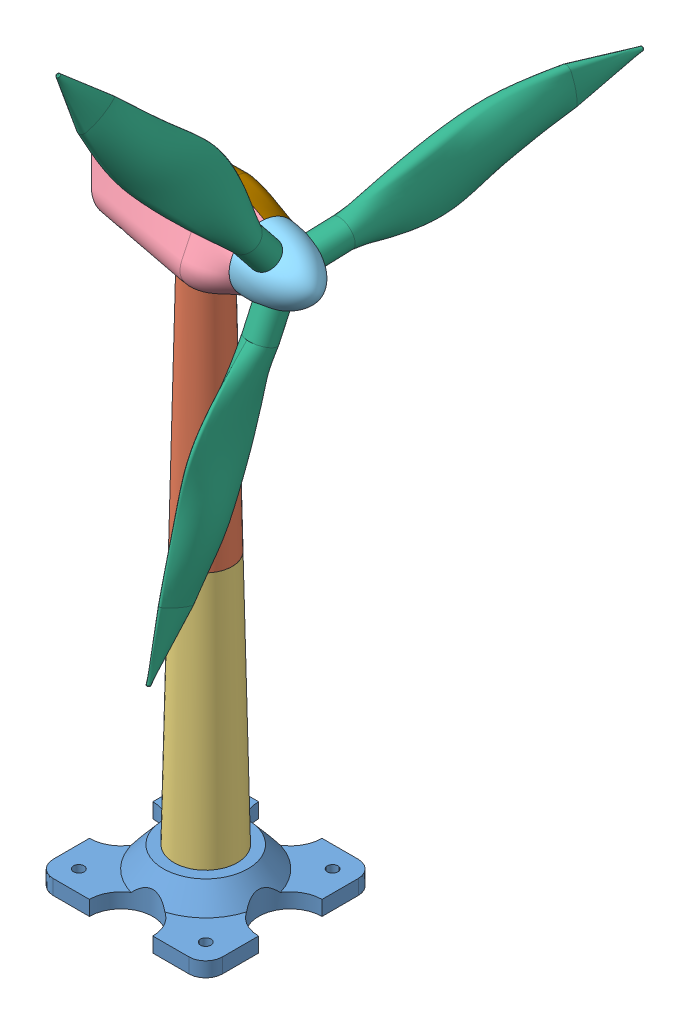
SolidWorks assembly Assem1, configuration Default. Lengths in mm.
Overall size (156.03 521.01 338.75).
12 component instances, 9 part files, 19 mates.
Components (placement in the parent):
- 1.Base-1: 1.Base [Default] at (0 0 89.5274) size (101.6 21.59 101.6)
- 5.Upper Mast-1: 5.Upper Mast [Default] at (0 173.99 89.5274) x (0 1 0) z (-0.807712 0 0.589577) size (165.1 31.76 31.76)
- Lower Mast-1: Lower Mast [Default] at (0 8.89 89.5274) x (0 1 0) z (0 0 1) size (165.1 38.1 38.1)
- 9.housing-1: 9.housing [Default] at (14.0969 349.25 91.06) x (0.108083 0 -0.994142) z (0.994142 0 0.108083) size (31.53 51.06 103.55)
- 2.Rotar-1: 2.Rotar [Default] at (39.3481 349.25 93.8053) x (-0.994142 0 -0.108083) z (0.015527 -0.989627 -0.142821) size (36.1 38.53 38.1)
- 3.Blade-1: 3.Blade [Default] at (52.7888 350.3447 87.6812) x (-0.956249 -0.256134 -0.141365) z (0.272301 -0.955906 -0.109981) size (18.53 190.5 45.27)
- 3.Blade-2: 3.Blade [Default] at (51.6687 342.172 97.9839) x (-0.986252 0.095866 0.134602) z (0.160329 0.357776 0.919941) size (18.53 190.5 45.27)
- 3.Blade-3: 3.Blade [Default] at (51.4637 355.2333 99.8689) x (-0.938302 0.160268 -0.306437) z (0.339279 0.598129 -0.726038) size (18.53 190.5 45.27)
- 6.Shaft-1: 6.Shaft [Default] at (51.9737 349.25 95.178) x (-0.108083 0 0.994142) z (-0.994142 0 -0.108083) size (9.65 9.65 85)
- 8.Washer-1: 8.Washer [Default] at (18.1267 349.25 91.4981) x (-0.07477 0.722104 0.687732) z (-0.994142 0 -0.108083) size (22.86 22.86 7.62)
- 8.Washer-2: 8.Washer [Default] at (-26.305 349.25 86.6676) x (-0.078498 0.687401 0.722023) z (-0.994142 0 -0.108083) size (22.86 22.86 7.62)
- Mirror9.housing-2: Mirror9.housing [Default] at (14.0969 349.25 91.06) x (-0.108083 0 0.994142) z (-0.994142 0 -0.108083) size (31.53 51.06 103.55)
Mates (geometry in assembly coordinates):
- Coincident3: coincident: plane of 1.Base-1 through (0 0 89.5274) normal (0 1 0); plane of assembly through (0 0 0) normal (0 1 0)
- Coincident4: coincident aligned: plane of 1.Base-1 through (0 0 89.5274) normal (1 0 0); plane of assembly through (0 0 0) normal (1 0 0)
- Concentric1: concentric anti-aligned: cylinder of 1.Base-1 through (0 0 89.5274) axis (0 1 0) radius 19.05; cylinder of Lower Mast-1 through (0 8.89 89.5274) axis (0 -1 0) radius 19.05
- Coincident5: coincident anti-aligned: plane of 1.Base-1 through (40.8 8.89 48.7274) normal (0 1 0); plane of Lower Mast-1 through (0 8.89 70.4774) normal (0 -1 0)
- Concentric2: concentric aligned: cone of 5.Upper Mast-1 through (0 326.39 89.5274) axis (0 1 0); cone of Lower Mast-1 through (0 173.99 89.5274) axis (0 1 0)
- Coincident6: coincident anti-aligned: plane of 5.Upper Mast-1 through (12.8265 173.99 80.1649) normal (0 -1 0); plane of Lower Mast-1 through (0 173.99 89.5274) normal (0 1 0)
- Concentric3: concentric anti-aligned: cylinder of 5.Upper Mast-1 through (0 173.99 89.5274) axis (0 -1 0) radius 4.83; cylinder of 9.housing-1 through (0 339.09 89.5274) axis (0 1 0) radius 4.83
- Tangent2: tangent: plane of 5.Upper Mast-1 through (3.9012 326.39 86.6798) normal (0 1 0); face of 9.housing-1
- Concentric4: concentric anti-aligned: cylinder of 9.housing-1 through (39.5902 349.25 93.8317) axis (0.994142 0 0.108083) radius 6.35; cylinder of 2.Rotar-1 through (51.9737 349.25 95.178) axis (-0.994142 0 -0.108083) radius 4.826
- Coincident7: coincident anti-aligned: plane of 9.housing-1 through (39.3481 349.25 93.8053) normal (0.994142 0 0.108083); plane of 2.Rotar-1 through (41.3858 351.9868 75.0634) normal (-0.994142 0 -0.108083)
- Coincident8: coincident anti-aligned: plane of 2.Rotar-1 through (52.7888 350.3447 87.6812) normal (0.106962 0.143663 -0.983829); plane of 3.Blade-1 through (52.7888 350.3447 87.6812) normal (-0.106962 -0.143663 0.983829)
- Concentric5: concentric anti-aligned: cylinder of 2.Rotar-1 through (52.7888 350.3447 87.6812) axis (0.106962 0.143663 -0.983829) radius 8.255; cylinder of 3.Blade-1 through (55.5056 353.9938 62.6919) axis (-0.106962 -0.143663 0.983829) radius 8.255
- Angle1: planar angle = 1.308997 rad anti-aligned: plane of 2.Rotar-1 through (39.3481 349.25 93.8053) normal (-0.994142 0 -0.108083); plane of 3.Blade-1 through (52.7888 350.3447 87.6812) normal (0.272301 -0.955906 -0.109981)
- Concentric6: concentric aligned: cylinder of 9.housing-1 through (39.5902 349.25 93.8317) axis (0.994142 0 0.108083) radius 6.35; cylinder of 6.Shaft-1 through (-32.5283 349.25 85.991) axis (0.994142 0 0.108083) radius 4.825
- Coincident10: coincident anti-aligned: plane of 2.Rotar-1 through (51.9737 349.25 95.178) normal (-0.994142 0 -0.108083); plane of 6.Shaft-1 through (51.9737 349.25 95.178) normal (0.994142 0 0.108083)
- Concentric7: concentric aligned: cylinder of 9.housing-1 through (39.5902 349.25 93.8317) axis (0.994142 0 0.108083) radius 11.43; cylinder of 8.Washer-1 through (10.5513 349.25 90.6746) axis (0.994142 0 0.108083) radius 11.43
- Coincident11: coincident anti-aligned: plane of 9.housing-1 through (18.1267 360.68 91.4981) normal (-0.994142 0 -0.108083); plane of 8.Washer-1 through (18.1267 349.25 91.4981) normal (0.994142 0 0.108083)
- Concentric8: concentric aligned: cylinder of 6.Shaft-1 through (-32.5283 349.25 85.991) axis (0.994142 0 0.108083) radius 4.825; cylinder of 8.Washer-2 through (-33.8804 349.25 85.844) axis (0.994142 0 0.108083) radius 11.43
- Coincident12: coincident anti-aligned: plane of 9.housing-1 through (-33.8804 355.6 85.844) normal (0.994142 0 0.108083); plane of 8.Washer-2 through (-33.8804 349.25 85.844) normal (-0.994142 0 -0.108083)
